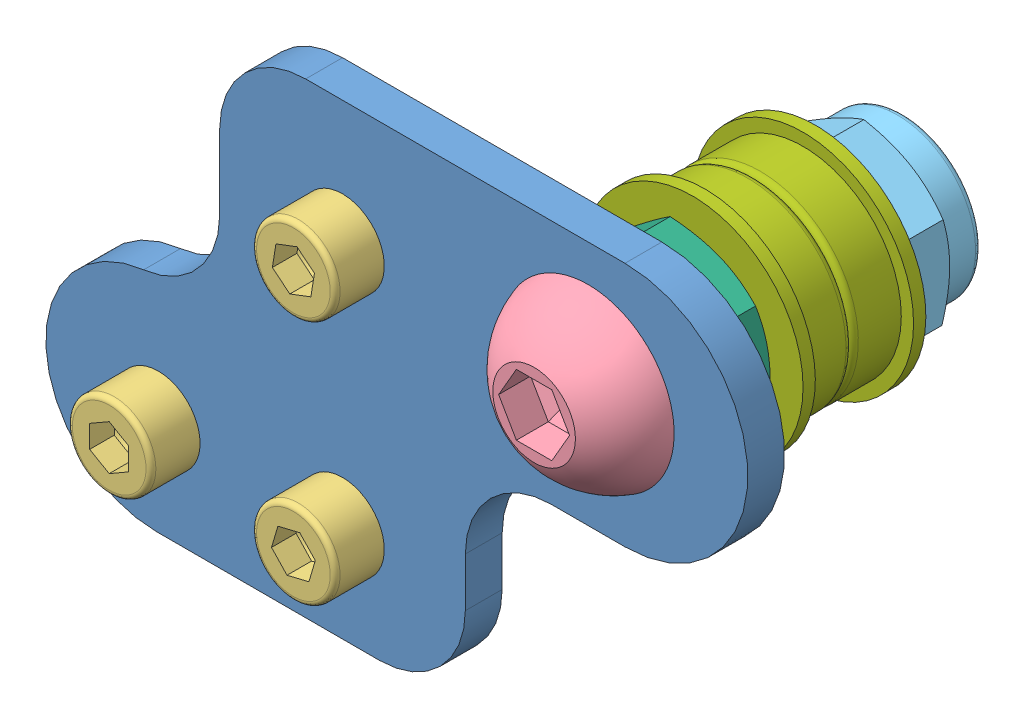
SolidWorks assembly ASM Y-Belt Tensioner, configuration Standard. Lengths in mm.
Overall size (57.16 40.7 30.9).
13 component instances, 7 part files, 20 mates.
Components (placement in the parent):
- Y Adjustment Block-1: Y Adjustment Block [Standard] x (1 0 0) z (0 1 0) size (57.16 3 38)
- M4 T-Slot Nut-1: M4 T-Slot Nut [Standard] at (-4 13 -1.1372) x (-1 0 0) z (0 0 -1) size (6 9.5 4.1)
- M4 T-Slot Nut-2: M4 T-Slot Nut [Standard] at (-19 -7 -1.1372) x (-1 0 0) z (0 0 -1) size (6 9.5 4.1)
- M4X8 Socket Head Screw-1: M4X8 Socket Head Screw [Standard] at (-19 -7 4.5001) x (0 0 -1) z (1 0 0) size (12 6.8 6.8)
- M4X8 Socket Head Screw-2: M4X8 Socket Head Screw [Standard] at (-4 13 4.5001) x (0 0 -1) z (0.987351 -0.158553 0) size (12 6.8 6.8)
- M4X8 Socket Head Screw-3: M4X8 Socket Head Screw [Standard] at (-4 -7 4.5001) x (0 0 -1) z (0.959125 -0.282984 0) size (12 6.8 6.8)
- M4 T-Slot Nut-3: M4 T-Slot Nut [Standard] at (-4 -7 -1.1372) x (-1 0 0) z (0 0 -1) size (6 9.5 4.1)
- ASM Roller Bolt-1: ASM Roller Bolt [Standard] at (16 13 8.9001) x (0 0 -1) z (1 0 0) size (30.9 25.4 25.4)
  - M8X25 Pan Head Screw-1: M8X25 Pan Head Screw [Standard] at origin size (30.62 14.79 14.79)
  - M8 Self-locking nut-1: M8 Self-locking nut [Standard] at (27.7325 0 0) x (0 0.488663 0.872473) z (1 0 0) size (15.01 13 7.18)
  - M8 nut-1: M8 nut [Standard] at (7.4 0 0) x (0 0.613039 0.790053) z (-1 0 0) size (15.01 13 5.5)
  - F688 pillow-1: F688 pillow [Standard] at (22.9 0 0) x (0 0.424513 0.905422) z (0 -0.905422 0.424513) size (18 5 18)
  - F688 pillow-2: F688 pillow [Standard] at (12.9 0 0) x (0 0.751639 -0.659574) z (0 -0.659574 -0.751639) size (18 5 18)
Mates (geometry in assembly coordinates):
- Konzentrisch1: concentric aligned: cylinder of Y Adjustment Block-1 through (-19 -7 6.5001) axis (0 0 1) radius 2.25; cylinder of M4 T-Slot Nut-2 through (-19 -7 -4.0662) axis (0 0 1) radius 2
- Konzentrisch3: concentric aligned: cylinder of Y Adjustment Block-1 through (-4 13 1.5001) axis (0 0 1) radius 2.25; cylinder of M4 T-Slot Nut-1 through (-4 13 -4.0662) axis (0 0 1) radius 2
- Konzentrisch4: concentric aligned: cylinder of Y Adjustment Block-1 through (-19 -7 6.5001) axis (0 0 1) radius 2.25; cylinder of M4X8 Socket Head Screw-1 through (-19 -7 5.4417) axis (0 0 1) radius 2
- Deckungsgleich11: coincident anti-aligned: plane of Y Adjustment Block-1 through (6.5 13 4.5001) normal (0 0 1); plane of M4X8 Socket Head Screw-1 through (-19 -3.6 4.5001) normal (0 0 -1)
- Deckungsgleich12: coincident anti-aligned: plane of Y Adjustment Block-1 through (6.5 13 4.5001) normal (0 0 1); plane of M4X8 Socket Head Screw-2 through (-3.4609 16.357 4.5001) normal (0 0 -1)
- Konzentrisch5: concentric aligned: cylinder of Y Adjustment Block-1 through (-4 13 1.5001) axis (0 0 1) radius 2.25; cylinder of M4X8 Socket Head Screw-2 through (-4 13 5.4417) axis (0 0 1) radius 2
- Deckungsgleich13: coincident anti-aligned: plane of Y Adjustment Block-1 through (6.5 13 4.5001) normal (0 0 1); plane of M4X8 Socket Head Screw-3 through (-3.0379 -3.739 4.5001) normal (0 0 -1)
- Konzentrisch6: concentric aligned: cylinder of Y Adjustment Block-1 through (-4 -7 6.5001) axis (0 0 1) radius 2.25; cylinder of M4X8 Socket Head Screw-3 through (-4 -7 5.4417) axis (0 0 1) radius 2
- Konzentrisch7: concentric aligned: cylinder of Y Adjustment Block-1 through (16 13 6.5001) axis (0 0 1) radius 4.05; cylinder of ASM Roller Bolt-1/M8X25 Pan Head Screw-1 through (16 13 -5.4999) axis (0 0 1) radius 4
- Deckungsgleich14: coincident anti-aligned: plane of Y Adjustment Block-1 through (6.5 13 4.5001) normal (0 0 1); plane of ASM Roller Bolt-1/M8X25 Pan Head Screw-1 through (16 13 4.5001) normal (0 0 -1)
- Konzentrisch31: concentric aligned: cylinder of Y Adjustment Block-1 through (-4 -7 6.5001) axis (0 0 1) radius 2.25; cylinder of M4 T-Slot Nut-3 through (-4 -7 -4.0662) axis (0 0 1) radius 2
- Parallel1: parallel aligned: plane of Y Adjustment Block-1 through (-14 23 1.5001) normal (-1 0 0); plane of M4 T-Slot Nut-1 through (-7 13 -1.1372) normal (-1 0 0)
- Parallel2: parallel aligned: plane of M4 T-Slot Nut-1 through (-7 13 -1.1372) normal (-1 0 0); plane of M4 T-Slot Nut-3 through (-7 -7 -1.1372) normal (-1 0 0)
- Parallel3: parallel aligned: plane of M4 T-Slot Nut-2 through (-22 -7 -1.1372) normal (-1 0 0); plane of M4 T-Slot Nut-3 through (-7 -7 -1.1372) normal (-1 0 0)
- Deckungsgleich15: coincident aligned: plane of M4 T-Slot Nut-2 through (-22 -11.75 -0.2999) normal (0 0 1); plane of M4 T-Slot Nut-3 through (-7 -11.75 -0.2999) normal (0 0 1)
- Deckungsgleich16: coincident aligned: plane of M4 T-Slot Nut-1 through (-7 8.25 -0.2999) normal (0 0 1); plane of M4 T-Slot Nut-3 through (-7 -11.75 -0.2999) normal (0 0 1)
- Abstand1: distance = 1.8 mm anti-aligned: plane of M4 T-Slot Nut-1 through (-7 8.25 -0.2999) normal (0 0 1); plane of Y Adjustment Block-1 through (6.5 13 1.5001) normal (0 0 -1)
- Deckungsgleich17: coincident aligned: plane of Y Adjustment Block-1 through (0 0 0) normal (0 1 0); plane of assembly through (0 0 0) normal (0 1 0)
- Deckungsgleich18: coincident aligned: plane of Y Adjustment Block-1; plane of assembly through (0 0 0) normal (1 0 0)
- Deckungsgleich19: coincident anti-aligned: plane of Y Adjustment Block-1 through (0 0 0) normal (0 0 -1); plane of assembly through (0 0 0) normal (0 0 1)
